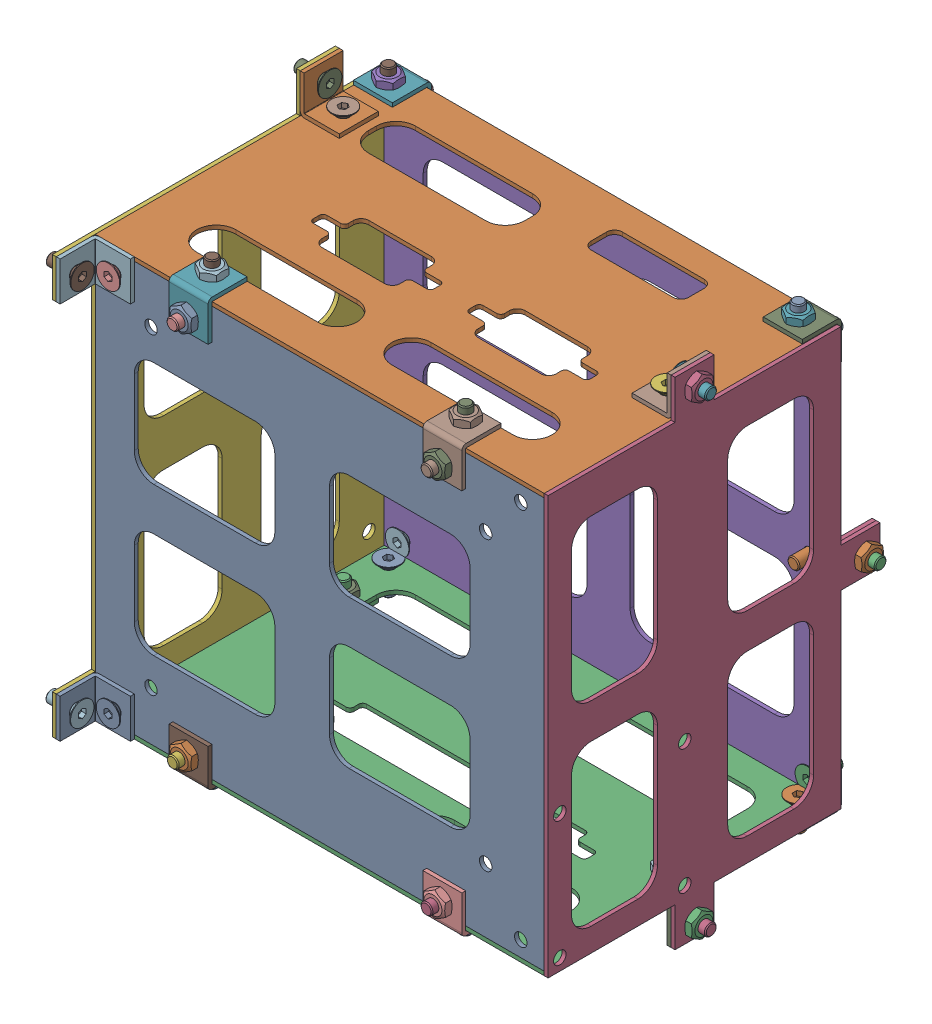
SolidWorks assembly PCB_board_box_reassemb, configuration Default. Lengths in mm.
Overall size (125.66 127 95).
76 component instances, 9 part files, 0 mates.
Components (placement in the parent):
- PCB_board_box_buttom-1: PCB_board_box_buttom [Default] at origin size (115 105 1)
- PCB_board_box_front-1: PCB_board_box_front [Default] at (0 53.5 -36.5) x (0 0 -1) z (0 -1 0) size (75 115 1)
- PCB_board_box_back-1: PCB_board_box_back [Default] at (0 -53.5 -36.5) x (0 0 1) z (0 1 0) size (75 115 1)
- PCB_board_box_right-1: PCB_board_box_right [Default] at (58.5 0 -36.5) x (0 0 1) z (-1 0 0) size (85 127 1)
- PCB_board_box_top-1: PCB_board_box_top [Default] at (0 0 -74) x (0 -1 0) z (0 0 1) size (105 115 1)
- PCB_board_box_left-1: PCB_board_box_left [Default] at (-57.5 0 -36.5) x (0 0 1) z (-1 0 0) size (85 127 1)
- connector_1-1: connector_1 [Default] at (-32.5 49.6 2.1) x (1 0 0) z (0 0 -1) size (10 10 10)
- connector_1-2: connector_1 [Default] at (57.5 58.5 -36.5) x (0 0 1) z (-1 0 0) size (10 10 10)
- connector_1-3: connector_1 [Default] at (57.5 -58.5 -36.5) x (0 0 -1) z (-1 0 0) size (10 10 10)
- connector_1-4: connector_1 [Default] at (32.5 -49.6 2.1) x (-1 0 0) z (0 0 -1) size (10 10 10)
- connector_1-5: connector_1 [Default] at (-32.5 -49.6 2.1) x (-1 0 0) z (0 0 -1) size (10 10 10)
- connector_1-6: connector_1 [Default] at (-57.5 48.5 6) x (0 1 0) z (1 0 0) size (10 10 10)
- connector_1-7: connector_1 [Default] at (-57.5 -48.5 6) x (0 1 0) z (1 0 0) size (10 10 10)
- connector_1-8: connector_1 [Default] at (-57.5 58.5 -56.5) x (0 0 -1) z (1 0 0) size (10 10 10)
- connector_1-9: connector_1 [Default] at (-57.5 -58.5 -56.5) x (0 0 1) z (1 0 0) size (10 10 10)
- connector_1-10: connector_1 [Default] at (52.5 0 -74) x (0 -1 0) z (0 0 -1) size (10 10 10)
- connector_1-11: connector_1 [Default] at (52.5 -49.6 -75.1) size (10 10 10)
- connector_1-12: connector_1 [Default] at (-52.5 -54.6 -70.1) x (-1 0 0) z (0 1 0) size (10 10 10)
- connector_1-13: connector_1 [Default] at (-52.5 49.6 -75.1) x (-1 0 0) z (0 0 1) size (10 10 10)
- connector_1-14: connector_1 [Default] at (32.5 49.6 2.1) x (1 0 0) z (0 0 -1) size (10 10 10)
- connector_1-15: connector_1 [Default] at (52.5 49.6 -75.1) x (-1 0 0) z (0 0 1) size (10 10 10)
- ISO 10642 - M3 x  8-1: ISO 10642 - M3 x  8 [Default] at (-52.5 48.6 -71.3293) x (0 0 -1) z (-1 0 0) size (8 6 6)
- ISO 10642 - M3 x  8-2: ISO 10642 - M3 x  8 [Default] at (-52.5 50.8293 -69.1) x (0 1 0) z (-1 0 0) size (8 6 6)
- ISO 10642 - M3 x  8-3: ISO 10642 - M3 x  8 [Default] at (-52.5 -48.6 -71.3293) x (0 0 -1) z (-1 0 0) size (8 6 6)
- ISO 10642 - M3 x  8-4: ISO 10642 - M3 x  8 [Default] at (-52.5 -50.8293 -69.1) x (0 -1 0) z (-1 0 0) size (8 6 6)
- ISO 10642 - M3 x  8-5: ISO 10642 - M3 x  8 [Default] at (52.5 -50.7586 -69.1) x (0 -1 0) z (-1 0 0) size (8 6 6)
- ISO 10642 - M3 x  8-6: ISO 10642 - M3 x  8 [Default] at (52.5 -48.6 -71.2586) x (0 0 -1) z (-1 0 0) size (8 6 6)
- ISO 10642 - M3 x  8-7: ISO 10642 - M3 x  8 [Default] at (32.5 -48.6 -1.7414) x (0 0 1) z (-1 0 0) size (8 6 6)
- ISO 10642 - M3 x  8-8: ISO 10642 - M3 x  8 [Default] at (32.5 -50.7586 -3.9) x (0 -1 0) z (-1 0 0) size (8 6 6)
- ISO 10642 - M3 x  8-9: ISO 10642 - M3 x  8 [Default] at (-32.5 -48.6 -1.7414) x (0 0 1) z (-1 0 0) size (8 6 6)
- ISO 10642 - M3 x  8-10: ISO 10642 - M3 x  8 [Default] at (-32.5 -50.7586 -3.9) x (0 -1 0) z (-1 0 0) size (8 6 6)
- ISO 10642 - M3 x  8-11: ISO 10642 - M3 x  8 [Default] at (32.5 48.6 -1.7414) x (0 0 1) z (-1 0 0) size (8 6 6)
- ISO 10642 - M3 x  8-12: ISO 10642 - M3 x  8 [Default] at (32.5 50.7586 -3.9) x (0 1 0) z (-1 0 0) size (8 6 6)
- ISO 10642 - M3 x  8-13: ISO 10642 - M3 x  8 [Default] at (-32.5 48.6 -1.6707) x (0 0 1) z (-1 0 0) size (8 6 6)
- ISO 10642 - M3 x  8-14: ISO 10642 - M3 x  8 [Default] at (-32.5 50.7586 -3.9) x (0 1 0) z (-1 0 0) size (8 6 6)
- ISO 10642 - M3 x  8-15: ISO 10642 - M3 x  8 [Default] at (52.5 48.6 -71.2586) x (0 0 -1) z (-1 0 0) size (8 6 6)
- ISO 10642 - M3 x  8-16: ISO 10642 - M3 x  8 [Default] at (52.5 50.7586 -69.1) x (0 1 0) z (-1 0 0) size (8 6 6)
- ISO 10642 - M3 x  8-17: ISO 10642 - M3 x  8 [Default] at (51.5 0 -76.7414) x (0 0 1) z (-1 0 0) size (8 6 6)
- ISO 10642 - M3 x  8-18: ISO 10642 - M3 x  8 [Default] at (54.7586 0 -80) x (1 0 0) z (0 0 -1) size (8 6 6)
- ISO 10642 - M3 x  8-19: ISO 10642 - M3 x  8 [Default] at (54.7586 -59.5 -36.5) x (1 0 0) z (0 0 -1) size (8 6 6)
- ISO 10642 - M3 x  8-20: ISO 10642 - M3 x  8 [Default] at (51.5 -56.2414 -36.5) x (0 1 0) z (-1 0 0) size (8 6 6)
- ISO 10642 - M3 x  8-21: ISO 10642 - M3 x  8 [Default] at (51.5 56.2414 -36.5) x (0 -1 0) z (-1 0 0) size (8 6 6)
- ISO 10642 - M3 x  8-22: ISO 10642 - M3 x  8 [Default] at (54.8293 59.5 -36.5) x (1 0 0) z (0 0 -1) size (8 6 6)
- ISO 10642 - M3 x  8-23: ISO 10642 - M3 x  8 [Default] at (-51.5 56.1707 -56.5) x (0 -1 0) z (-1 0 0) size (8 6 6)
- ISO 10642 - M3 x  8-24: ISO 10642 - M3 x  8 [Default] at (-54.8293 59.5 -56.5) x (-1 0 0) z (0 0 1) size (8 6 6)
- ISO 10642 - M3 x  8-25: ISO 10642 - M3 x  8 [Default] at (-51.5 48.5 3.7414) x (0 0 -1) z (-1 0 0) size (8 6 6)
- ISO 10642 - M3 x  8-26: ISO 10642 - M3 x  8 [Default] at (-54.7586 48.5 7) x (-1 0 0) z (0 0 1) size (8 6 6)
- ISO 10642 - M3 x  8-27: ISO 10642 - M3 x  8 [Default] at (-54.8293 -48.5 7) x (-1 0 0) z (0 0 1) size (8 6 6)
- ISO 10642 - M3 x  8-28: ISO 10642 - M3 x  8 [Default] at (-51.5 -48.5 3.7414) x (0 0 -1) z (-1 0 0) size (8 6 6)
- ISO 10642 - M3 x  8-29: ISO 10642 - M3 x  8 [Default] at (-54.7586 -59.5 -56.5) x (-1 0 0) z (0 0 1) size (8 6 6)
- ISO 10642 - M3 x  8-30: ISO 10642 - M3 x  8 [Default] at (-51.5 -56.1707 -56.5) x (0 1 0) z (-1 0 0) size (8 6 6)
- ISO 4032 - M3-1: ISO 4032 - M3 [Default] at (-52.5 48.6 -77.5) x (0 0 1) z (-1 0 0) size (2.4 6.35 5.5)
- ISO 4032 - M3-2: ISO 4032 - M3 [Default] at (-52.5 54.6 -69.1) x (0 1 0) z (-1 0 0) size (2.4 6.35 5.5)
- ISO 4032 - M3-3: ISO 4032 - M3 [Default] at (-51.5 52.5 -56.5) x (0 -1 0) z (-1 0 0) size (2.4 6.35 5.5)
- ISO 4032 - M3-4: ISO 4032 - M3 [Default] at (-52.5 -48.6 -75.1) x (0 0 -1) z (-1 0 0) size (2.4 6.35 5.5)
- ISO 4032 - M3-5: ISO 4032 - M3 [Default] at (-52.5 -54.6 -69.1) x (0 -1 0) z (-1 0 0) size (2.4 6.35 5.5)
- ISO 4032 - M3-6: ISO 4032 - M3 [Default] at (-51.5 -52.5 -56.5) x (0 1 0) z (-1 0 0) size (2.4 6.35 5.5)
- ISO 4032 - M3-7: ISO 4032 - M3 [Default] at (-51.5 -48.5 0) x (0 0 -1) z (-1 0 0) size (2.4 6.35 5.5)
- ISO 4032 - M3-8: ISO 4032 - M3 [Default] at (-51.5 48.5 0) x (0 0 -1) z (-1 0 0) size (2.4 6.35 5.5)
- ISO 4032 - M3-9: ISO 4032 - M3 [Default] at (-32.5 57 -3.9) x (0 -1 0) z (-1 0 0) size (2.4 6.35 5.5)
- ISO 4032 - M3-10: ISO 4032 - M3 [Default] at (-32.5 48.6 4.5) x (0 0 -1) z (-1 0 0) size (2.4 6.35 5.5)
- ISO 4032 - M3-11: ISO 4032 - M3 [Default] at (-32.5 -48.6 2.1) x (0 0 1) z (-1 0 0) size (2.4 6.35 5.5)
- ISO 4032 - M3-12: ISO 4032 - M3 [Default] at (-32.5 -57 -3.9) x (0 1 0) z (-1 0 0) size (2.4 6.35 5.5)
- ISO 4032 - M3-13: ISO 4032 - M3 [Default] at (52.5 -48.6 -75.1) x (0 0 -1) z (-1 0 0) size (2.4 6.35 5.5)
- ISO 4032 - M3-14: ISO 4032 - M3 [Default] at (52.5 -54.6 -69.1) x (0 -1 0) z (-1 0 0) size (2.4 6.35 5.5)
- ISO 4032 - M3-15: ISO 4032 - M3 [Default] at (52.5 48.6 -75.1) x (0 0 -1) z (-1 0 0) size (2.4 6.35 5.5)
- ISO 4032 - M3-16: ISO 4032 - M3 [Default] at (52.5 54.6 -69.1) x (0 1 0) z (-1 0 0) size (2.4 6.35 5.5)
- ISO 4032 - M3-17: ISO 4032 - M3 [Default] at (32.5 57 -3.9) x (0 -1 0) z (-1 0 0) size (2.4 6.35 5.5)
- ISO 4032 - M3-18: ISO 4032 - M3 [Default] at (32.5 48.6 4.5) x (0 0 -1) z (-1 0 0) size (2.4 6.35 5.5)
- ISO 4032 - M3-19: ISO 4032 - M3 [Default] at (32.5 -48.6 4.5) x (0 0 -1) z (-1 0 0) size (2.4 6.35 5.5)
- ISO 4032 - M3-20: ISO 4032 - M3 [Default] at (32.5 -57 -3.9) x (0 1 0) z (-1 0 0) size (2.4 6.35 5.5)
- ISO 4032 - M3-21: ISO 4032 - M3 [Default] at (51.5 -52.5 -36.5) x (0 1 0) z (-1 0 0) size (2.4 6.35 5.5)
- ISO 4032 - M3-22: ISO 4032 - M3 [Default] at (51.5 52.5 -36.5) x (0 -1 0) z (-1 0 0) size (2.4 6.35 5.5)
- ISO 4032 - M3-23: ISO 4032 - M3 [Default] at (58.5 0 -80) size (2.4 6.35 5.5)
- ISO 4032 - M3-24: ISO 4032 - M3 [Default] at (58.5 -59.5 -36.5) size (2.4 6.35 5.5)
- ISO 4032 - M3-25: ISO 4032 - M3 [Default] at (58.5 59.5 -36.5) size (2.4 6.35 5.5)
